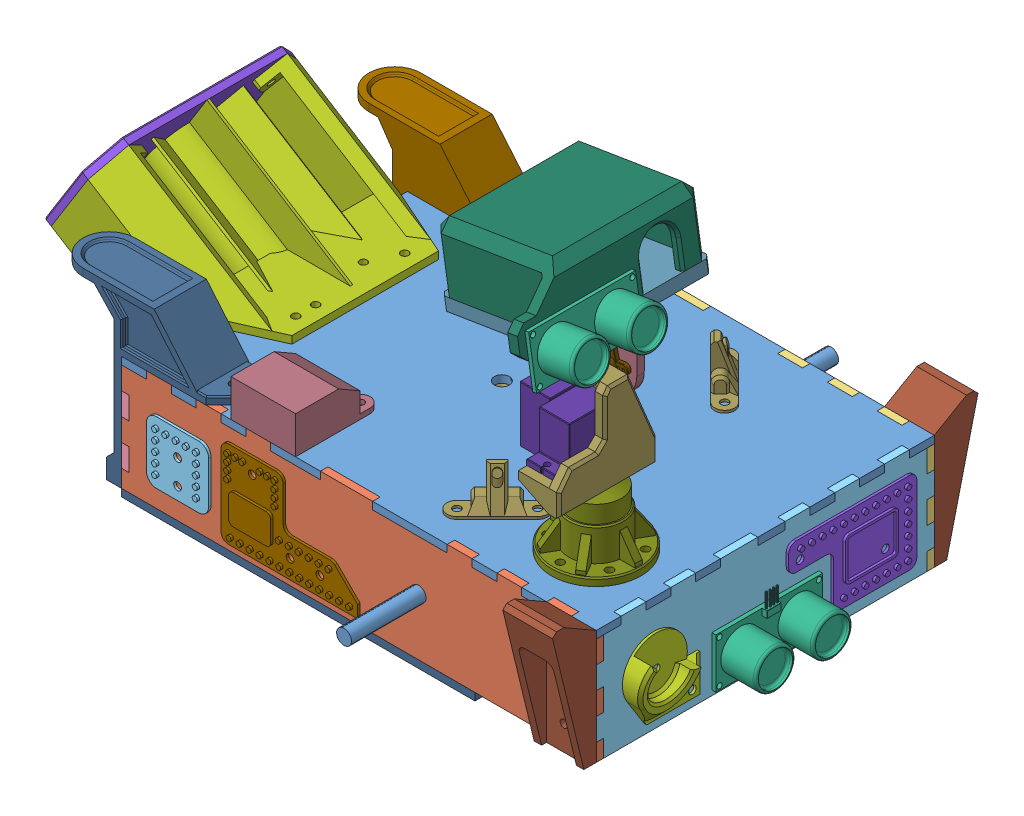
SolidWorks assembly bodySub-2, configuration Default. Lengths in mm.
Overall size (271.51 168.8 196).
43 component instances, 33 part files, 108 mates.
Components (placement in the parent):
- body-top-1: body-top [Default] at (-43.052 0 151.6865) x (1 0 0) z (0 1 0) size (191 136 3)
- body-right-1: body-right [Default] at (-43.052 -43 148.6865) size (191 46 3)
- body-left-1: body-left [Default] at (-43.052 -43 18.6865) x (-1 0 0) z (0 0 -1) size (191 46 3)
- body-rear-1: body-rear [Default] at (-43.052 -43 15.6865) x (0 0 -1) z (1 0 0) size (136 46 3)
- body-front-1: body-front [Default] at (147.948 -43 15.6865) x (0 0 1) z (-1 0 0) size (136 46 3)
- usSensor-1: usSensor [Default] at (-46.052 -45.55 62.1865) x (0 0 1) z (0 -1 0) size (43 15.6 26)
- usSensor-2: usSensor [Default] at (147.948 -21 62.1865) x (0 0 1) z (0 1 0) size (43 15.6 26)
- power-1: power [Default] at (-43.052 -43 151.6865) x (0 0 1) z (-1 0 0) size (84 85.03 90.67)
- powerCap-1: powerCap [Default] at (-74.8205 44.2822 15.6865) x (0 0 -1) z (-0.848048 0.529919 0) size (84 51.88 5)
- powerShoulder-left-1: powerShoulder-left [Default] at (-43.052 -43 15.6865) x (-1 0 0) z (0 0 -1) size (66.06 69 21)
- powerShoulder-right-1: powerShoulder-right [Default] at (-43.052 -43 109.6865) x (-1 0 0) z (0 0 -1) size (66.06 69 21)
- shoulder-1: shoulder [Default] at (127.948 -43 151.6865) size (20 53.5 17.6)
- shoulder-2: shoulder [Default] at (147.948 -43 15.6865) x (-1 0 0) z (0 0 -1) size (20 53.5 17.6)
- headSub-1: headSub [Default] at (131.8571 34.2972 110.6077) size (71.32 113.8 76.5) (flexible)
  - headServoMount-1: headServoMount [Default] at (-5.7591 24.2018 7.3288) x (0 0 1) z (1 0 0) size (39.75 36.12 28.6)
  - headMount-1: headMount [Default] at (-19.6139 25.1697 -5.5142) x (0.16009 -0.987102 0) z (0 0 -1) size (40 30 34)
  - headBaseplate-1: headBaseplate [Default] at (-50.728 44.8869 -23.5142) x (0 0 1) z (-0.987102 -0.16009 0) size (60 5 50)
  - headCanopy-1: headCanopy [Default] at (-6.1756 82.5045 -23.5142) x (0 0 1) z (0.16009 -0.987102 0) size (76.5 50 25)
  - usSensor-2: usSensor [Default] at (-0.5725 47.9559 49.9858) x (0 0 -1) z (0.16009 -0.987102 0) size (43 15.6 26)
  - mastMount-top-1: mastMount-top [Default] at (-11.9091 -31.2972 13.0788) size (36 28 36)
  - sg90Servo-1: sg90Servo [Default] at (-5.7591 24.0708 7.3288) x (0 0 1) z (1 0 0) size (32.7 29.37 12.3)
  - sg90Servo-2: sg90Servo [Default] at (-18.0591 24.5458 25.4538) x (0 -1 0) z (1 0 0) size (32.7 29.37 12.3)
  - sg90ServoHorn-star-1: sg90ServoHorn-star [Default] at (-27.3265 20.2151 -5.5142) x (0.16009 -0.987102 0) z (-0.987102 -0.16009 0) size (34.4 4 15.7)
- pivotAxle-1: pivotAxle [Default] at (76.448 -20 181.6865) x (-0.972905 0.231206 0) z (-0.231206 -0.972905 0) size (6 196 6)
- edison-arduino-1: edison-arduino [Default] at (-30.752 -13.38 66.6865) x (1 0 0) z (0 0 -1) size (127.2 12.67 72)
- diffMount-mid-1: diffMount-mid [Default] at (-43.052 0 151.6865) x (-1 0 0) z (0 -1 0) size (30 30 3)
- diffMount-bottom-1: diffMount-bottom [Default] at (-43.052 -3 151.6865) x (-1 0 0) z (0 -1 0) size (30 30 3)
- sideDetailA-left-1: sideDetailA-left [Default] at (-43.052 -43 15.6865) x (-1 0 0) z (0 0 -1) size (25 25 2)
- sideDetailB-1: sideDetailB [Default] at (-43.052 -43 15.6865) x (-1 0 0) z (0 0 -1) size (55 35 2)
- fontDetailA-1: fontDetailA [Default] at (147.948 -43 15.6865) x (0 0 -1) z (1 0 0) size (30.16 30.17 9.09)
- frontDetailB-1: frontDetailB [Default] at (147.948 -43 15.6865) x (0 0 -1) z (1 0 0) size (51.58 33 2)
- sideDetailB-mirr-1: sideDetailB-mirr [Default] at (-43.052 -43 151.6865) x (-1 0 0) z (0 0 -1) size (55 35 2)
- sideDetailA-left-2: sideDetailA-left [Default] at (3.948 -43 151.6865) size (25 25 2)
- bodyUnderCover-1: bodyUnderCover [Default] at (99.148 -43 15.6865) x (1 0 0) z (0 -1 0) size (142.2 136 9)
- underCoverMagnetMount-front-1: underCoverMagnetMount-front [Default] at (99.148 -43 15.6865) x (-1 0 0) z (0 1 0) size (7 7 11.3)
- underCoverMagnetMount-front-2: underCoverMagnetMount-front [Default] at (89.148 -43 151.6865) x (1 0 0) z (0 1 0) size (7 7 11.3)
- underCoverMagnetMount-front-3: underCoverMagnetMount-front [Default] at (-31.552 -43 15.6865) x (-1 0 0) z (0 1 0) size (7 7 11.3)
- underCoverMagnetMount-front-4: underCoverMagnetMount-front [Default] at (-41.552 -43 151.6865) x (1 0 0) z (0 1 0) size (7 7 11.3)
- topDetailA-1: topDetailA [Default] at (-43.052 3 151.6865) x (1 0 0) z (0 1 0) size (24.26 24.26 16)
- topDetailA-2: topDetailA [Default] at (108.7154 3 168.7548) x (0 0 -1) z (0 1 0) size (24.26 24.26 16)
- topDetailB-1: topDetailB [Default] at (-43.052 3 151.6865) x (1 0 0) z (0 1 0) size (26 34 15)
- topDetailCA-1: topDetailCA [Default] at (-46.5393 3 149.9052) x (1 0 0) z (0 1 0) size (20.56 18.54 22.66)
- topDetailCB-1: topDetailCB [Default] at (1.7026 61.1918 61.409) x (0.910046 -0.22774 0.34634) z (0.414508 0.5 -0.760384) size (46.65 24.53 4)
Mates (geometry in assembly coordinates):
- Coincident23: coincident anti-aligned: plane of body-front-1 through (147.948 -43 15.6865) normal (1 0 0); plane of usSensor-2 through (147.948 -21 62.1865) normal (-1 0 0)
- Coincident22: coincident anti-aligned: plane of body-top-1 through (144.948 -0.001 141.6865) normal (1 0 0); plane of body-front-1 through (144.948 -43 15.6865) normal (-1 0 0)
- Coincident21: coincident anti-aligned: plane of body-top-1 through (147.948 -0.001 141.6865) normal (0 0 -1); plane of body-front-1 through (147.949 -43 141.6865) normal (0 0 1)
- Coincident17: coincident anti-aligned: plane of body-top-1 through (-40.052 -0.001 35.6865) normal (-1 0 0); plane of body-rear-1 through (-40.052 -43 15.6865) normal (1 0 0)
- Coincident16: coincident anti-aligned: plane of body-top-1 through (-43.052 -0.001 25.6865) normal (0 0 1); plane of body-rear-1 through (-43.053 -43 25.6865) normal (0 0 -1)
- Coincident12: coincident anti-aligned: plane of body-top-1 through (-43.052 -0.001 18.6865) normal (0 0 -1); plane of body-left-1 through (-43.052 -43 18.6865) normal (0 0 1)
- Coincident11: coincident anti-aligned: plane of body-top-1 through (137.948 -0.001 15.6865) normal (-1 0 0); plane of body-left-1 through (137.948 3 15.6855) normal (1 0 0)
- Coincident7: coincident anti-aligned: plane of body-top-1 through (-43.052 -0.001 148.6865) normal (0 0 1); plane of body-right-1 through (-43.052 -43 148.6865) normal (0 0 -1)
- Coincident6: coincident anti-aligned: plane of body-top-1 through (-33.052 -0.001 151.6865) normal (1 0 0); plane of body-right-1 through (-33.052 0 151.6875) normal (-1 0 0)
- Coincident2: coincident anti-aligned: plane of body-top-1 through (-43.052 0 151.6865) normal (0 -1 0); plane of assembly through (0 0 0) normal (0 1 0)
- Concentric3: concentric aligned: cylinder of body-front-1 through (144.948 -22.5 103.6865) axis (1 0 0) radius 1.05; cylinder of usSensor-2 through (147.947 -22.5 103.6865) axis (1 0 0) radius 1.05
- Concentric4: concentric aligned: cylinder of body-front-1 through (144.948 -39.5 63.6865) axis (1 0 0) radius 1.05; cylinder of usSensor-2 through (147.947 -39.5 63.6865) axis (1 0 0) radius 1.05
- Coincident24: coincident anti-aligned: plane of power-1 through (-46.052 -43 151.6865) normal (-1 0 0); plane of usSensor-1 through (-46.052 -45.55 62.1865) normal (1 0 0)
- Concentric5: concentric anti-aligned: cylinder of body-top-1 through (-19.052 3 105.6173) axis (0 -1 0) radius 1.55; cylinder of power-1 through (-19.052 -43.001 105.6173) axis (0 1 0) radius 1.55
- Coincident25: coincident anti-aligned: plane of body-top-1 through (-43.052 3 151.6865) normal (0 1 0); plane of power-1 through (-13.052 3 151.6865) normal (0 -1 0)
- Concentric8: concentric aligned: cylinder of body-rear-1 through (-40.052 -27.05 63.6865) axis (-1 0 0) radius 1.05; cylinder of power-1 through (-40.0822 -27.05 63.6865) axis (-1 0 0) radius 1.05
- Concentric9: concentric aligned: cylinder of power-1 through (-40.0822 -27.05 63.6865) axis (-1 0 0) radius 1.05; cylinder of usSensor-1 through (-46.051 -27.05 63.6865) axis (-1 0 0) radius 1.05
- Concentric10: concentric aligned: cylinder of usSensor-1 through (-46.051 -27.05 103.6865) axis (-1 0 0) radius 1.05; cylinder of power-1 through (-40.0822 -27.05 103.6865) axis (-1 0 0) radius 1.05
- Coincident26: coincident anti-aligned: plane of power-1 through (-105.1238 -4.2132 151.6865) normal (-0.848048 0.529919 0); plane of powerCap-1 through (-74.8205 44.2822 15.6865) normal (0.848048 -0.529919 0)
- Concentric11: concentric anti-aligned: cylinder of powerCap-1 through (-83.4594 36.1202 56.0789) axis (0.848048 -0.529919 0) radius 1.55; cylinder of power-1 through (2.7341 -17.7395 56.0789) axis (-0.848048 0.529919 0) radius 1.55
- Concentric12: concentric anti-aligned: cylinder of power-1 through (2.7341 -17.7395 111.2941) axis (-0.848048 0.529919 0) radius 1.55; cylinder of powerCap-1 through (-83.4594 36.1202 111.2941) axis (0.848048 -0.529919 0) radius 1.55
- Coincident27: coincident anti-aligned: plane of body-rear-1 through (-43.052 -43 15.6865) normal (-1 0 0); plane of powerShoulder-right-1 through (-43.052 -43 151.6865) normal (1 0 0)
- Coincident28: coincident anti-aligned: plane of body-top-1 through (-43.052 3 151.6865) normal (0 1 0); plane of powerShoulder-right-1 through (-43.052 3 81.1263) normal (0 -1 0)
- Concentric13: concentric anti-aligned: cylinder of body-top-1 through (-8.052 3 135.6865) axis (0 -1 0) radius 1.55; cylinder of powerShoulder-right-1 through (-8.052 -43.001 135.6865) axis (0 1 0) radius 1.55
- Coincident29: coincident anti-aligned: plane of body-rear-1 through (-43.052 -43 15.6865) normal (-1 0 0); plane of powerShoulder-left-1 through (-43.052 -43 15.6865) normal (1 0 0)
- Coincident30: coincident anti-aligned: plane of body-top-1 through (-43.052 3 151.6865) normal (0 1 0); plane of powerShoulder-left-1 through (-43.052 3 86.2467) normal (0 -1 0)
- Concentric14: concentric anti-aligned: cylinder of body-top-1 through (-8.052 3 31.6865) axis (0 -1 0) radius 1.55; cylinder of powerShoulder-left-1 through (-8.052 -43.001 31.6865) axis (0 1 0) radius 1.55
- Coincident31: coincident anti-aligned: plane of body-left-1 through (-43.052 -43 15.6865) normal (0 0 -1); plane of shoulder-2 through (127.948 -43 15.6865) normal (0 0 1)
- Concentric15: concentric anti-aligned: cylinder of body-left-1 through (137.948 -13 15.6865) axis (0 0 1) radius 1.55; cylinder of shoulder-2 through (137.948 -13 12.6865) axis (0 0 -1) radius 1.55
- Concentric16: concentric anti-aligned: cylinder of body-left-1 through (137.948 -33 15.6865) axis (0 0 1) radius 1.55; cylinder of shoulder-2 through (137.948 -33 12.6865) axis (0 0 -1) radius 1.55
- Coincident32: coincident anti-aligned: plane of body-right-1 through (-43.052 -43 151.6865) normal (0 0 1); plane of shoulder-1 through (147.948 -43 151.6865) normal (0 0 -1)
- Concentric17: concentric anti-aligned: cylinder of body-right-1 through (137.948 -13 151.6865) axis (0 0 -1) radius 1.55; cylinder of shoulder-1 through (137.948 -13 154.6865) axis (0 0 1) radius 1.55
- Concentric18: concentric anti-aligned: cylinder of body-right-1 through (137.948 -33 151.6865) axis (0 0 -1) radius 1.55; cylinder of shoulder-1 through (137.948 -33 154.6865) axis (0 0 1) radius 1.55
- Coincident33: coincident anti-aligned: plane of body-top-1 through (-43.052 3 151.6865) normal (0 1 0); plane of headSub-1/mastMount-top-1 through (119.948 3 123.6865) normal (0 -1 0)
- Concentric19: concentric anti-aligned: cylinder of body-top-1 through (132.5054 3 116.4365) axis (0 -1 0) radius 1.55; cylinder of headSub-1/mastMount-top-1 through (132.5054 6 116.4365) axis (0 1 0) radius 1.55
- Concentric20: concentric anti-aligned: cylinder of body-top-1 through (107.3906 3 130.9365) axis (0 -1 0) radius 1.55; cylinder of headSub-1/mastMount-top-1 through (107.3906 6 130.9365) axis (0 1 0) radius 1.55
- Coincident34: coincident aligned: plane of body-top-1 through (-43.052 3 151.6865) normal (0 1 0); plane of body-front-1 through (144.948 3 151.6865) normal (0 1 0)
- Coincident35: coincident aligned: plane of body-top-1 through (-43.052 3 151.6865) normal (0 1 0); plane of body-left-1 through (-43.052 3 15.6865) normal (0 1 0)
- Coincident36: coincident aligned: plane of body-top-1 through (-43.052 3 151.6865) normal (0 1 0); plane of body-rear-1 through (-40.052 3 15.6865) normal (0 1 0)
- Coincident37: coincident aligned: plane of body-top-1 through (-43.052 3 151.6865) normal (0 1 0); plane of body-right-1 through (147.948 3 151.6865) normal (0 1 0)
- Concentric21: concentric anti-aligned: cylinder of body-left-1 through (76.448 -20 18.6875) axis (0 0 -1) radius 3; cylinder of pivotAxle-1 through (76.448 -20 -14.3135) axis (0 0 1) radius 3
- Symmetric2: symmetric aligned: plane of body-top-1 through (-43.052 0 83.6865) normal (0 0 -1); plane of pivotAxle-1 through (76.448 -20 -14.3135) normal (0 0 -1); plane of pivotAxle-1 through (76.448 -20 181.6865) normal (0 0 1)
- Parallel1: parallel anti-aligned: plane of body-top-1 through (-43.052 0 151.6865) normal (0 -1 0); plane of edison-arduino-1 through (-30.752 -13.38 66.6865) normal (0 1 0)
- Parallel2: parallel anti-aligned: plane of body-rear-1 through (-40.052 -43 15.6865) normal (1 0 0); plane of edison-arduino-1 through (-30.752 -15 66.6865) normal (-1 0 0)
- Distance2: distance = 2 mm anti-aligned: plane of edison-arduino-1 through (-30.752 -15 66.6865) normal (0 -1 0); cylinder of pivotAxle-1 through (76.448 -20 -14.3135) axis (0 0 1) radius 3
- Distance3: distance = 1 mm anti-aligned: plane of edison-arduino-1 through (80.448 -26 134.6865) normal (-1 0 0); cylinder of pivotAxle-1 through (76.448 -20 -14.3135) axis (0 0 1) radius 3
- Distance4: distance = 10 mm anti-aligned: plane of edison-arduino-1 through (-30.752 -15 138.6865) normal (0 0 1); plane of body-right-1 through (-43.052 -43 148.6865) normal (0 0 -1)
- InPlace1: in place: plane of body-top-1 through (-43.052 0 151.6865) normal (0 -1 0); plane of ? through (0 0 0) normal (0 -1 0); moOrthogonalPlaneRef_w of body-top-1 through (-43.052 0 151.6865) normal (0 -1 0); unknown of ?; plane of body-top-1 through (-43.052 0 151.6865) normal (0 -1 0); line of ? through (55 -55 0) axis (0 0 -1); plane of body-top-1 through (-43.052 0 151.6865) normal (0 -1 0); unknown of diffMount-mid-1
- Coincident41: coincident aligned: plane of body-top-1; plane of diffMount-mid-1
- Coincident42: coincident aligned: moOrthogonalPlaneRef_w of body-top-1 through (-43.052 0 151.6865) normal (0 0 -1); plane of diffMount-mid-1
- Coincident43: coincident anti-aligned: moOrthogonalPlaneRef_w of body-top-1 through (-43.052 0 151.6865) normal (1 0 0); plane of diffMount-mid-1
- InPlace2: in place: plane of diffMount-mid-1 through (41.948 -3 83.6865) normal (0 -1 0); plane of ? through (0 -3 0) normal (0 -1 0); plane of diffMount-mid-1 through (41.948 -3 83.6865) normal (0 -1 0); unknown of ?; plane of diffMount-mid-1 through (41.948 -3 83.6865) normal (0 -1 0); line of ? through (-55 0 -3) axis (0 -1 0); plane of diffMount-mid-1 through (41.948 -3 83.6865) normal (0 -1 0); unknown of diffMount-bottom-1
- Coincident44: coincident aligned: plane of diffMount-mid-1; plane of diffMount-bottom-1
- Coincident45: coincident aligned: moOrthogonalPlaneRef_w of diffMount-mid-1 through (-43.052 -3 151.6865) normal (0 0 -1); plane of diffMount-bottom-1
- Coincident46: coincident anti-aligned: moOrthogonalPlaneRef_w of diffMount-mid-1 through (-43.052 -3 151.6865) normal (1 0 0); plane of diffMount-bottom-1
- InPlace3: in place: plane of body-left-1 through (-43.052 -43 15.6865) normal (0 0 -1); plane of ? through (0 0 15.6865) normal (0 0 -1); plane of body-left-1 through (-43.052 -43 15.6865) normal (0 0 -1); unknown of ?; plane of body-left-1 through (-43.052 -43 15.6865) normal (0 0 -1); plane of ? through (0 0 15.6865) normal (-1 0 0); plane of body-left-1 through (-43.052 -43 15.6865) normal (0 0 -1); unknown of ?
- Coincident47: coincident aligned: plane of body-left-1; plane of sideDetailA-left-1
- Coincident48: coincident aligned: moOrthogonalPlaneRef_w of body-left-1 through (-43.052 -43 15.6865) normal (0 1 0); plane of sideDetailA-left-1
- Coincident49: coincident anti-aligned: moOrthogonalPlaneRef_w of body-left-1 through (-43.052 -43 15.6865) normal (1 0 0); plane of sideDetailA-left-1 through (-43.052 -43 15.6865) normal (-1 0 0)
- InPlace4: in place: plane of body-left-1 through (-43.052 -43 15.6865) normal (0 0 -1); plane of ? through (0 0 15.6865) normal (0 0 -1); plane of body-left-1 through (-43.052 -43 15.6865) normal (0 0 -1); unknown of ?; plane of body-left-1 through (-43.052 -43 15.6865) normal (0 0 -1); plane of ? through (0 0 15.6865) normal (-1 0 0); plane of body-left-1 through (-43.052 -43 15.6865) normal (0 0 -1); unknown of ?
- Coincident50: coincident aligned: plane of body-left-1; plane of sideDetailB-1
- Coincident51: coincident aligned: moOrthogonalPlaneRef_w of body-left-1 through (-43.052 -43 15.6865) normal (0 1 0); plane of sideDetailB-1
- Coincident52: coincident anti-aligned: moOrthogonalPlaneRef_w of body-left-1 through (-43.052 -43 15.6865) normal (1 0 0); plane of sideDetailB-1 through (-43.052 -43 15.6865) normal (-1 0 0)
- InPlace5: in place: plane of body-front-1 through (147.948 -43 15.6865) normal (1 0 0); plane of ? through (147.948 0 0) normal (1 0 0); plane of body-front-1 through (147.948 -43 15.6865) normal (1 0 0); line of ? through (-55 147.948 0) axis (0 0 1); plane of body-front-1 through (147.948 -43 15.6865) normal (1 0 0); plane of ? through (147.948 0 0) normal (0 0 -1); plane of body-front-1 through (147.948 -43 15.6865) normal (1 0 0); unknown of ?
- Coincident53: coincident aligned: plane of body-front-1; plane of fontDetailA-1
- Coincident54: coincident aligned: moOrthogonalPlaneRef_w of body-front-1 through (147.948 -43 15.6865) normal (0 1 0); plane of fontDetailA-1
- Coincident55: coincident anti-aligned: moOrthogonalPlaneRef_w of body-front-1 through (147.948 -43 15.6865) normal (0 0 1); plane of fontDetailA-1 through (147.948 -43 15.6865) normal (0 0 -1)
- InPlace6: in place: plane of body-front-1 through (147.948 -43 15.6865) normal (1 0 0); plane of ? through (147.948 0 0) normal (1 0 0); plane of body-front-1 through (147.948 -43 15.6865) normal (1 0 0); line of ? through (-55 147.948 0) axis (0 0 1); plane of body-front-1 through (147.948 -43 15.6865) normal (1 0 0); plane of ? through (147.948 0 0) normal (0 0 -1); plane of body-front-1 through (147.948 -43 15.6865) normal (1 0 0); unknown of ?
- Coincident56: coincident aligned: plane of body-front-1; plane of frontDetailB-1
- Coincident57: coincident aligned: moOrthogonalPlaneRef_w of body-front-1 through (147.948 -43 15.6865) normal (0 1 0); plane of frontDetailB-1
- Coincident58: coincident anti-aligned: moOrthogonalPlaneRef_w of body-front-1 through (147.948 -43 15.6865) normal (0 0 1); plane of frontDetailB-1 through (147.948 -43 15.6865) normal (0 0 -1)
- Coincident59: coincident anti-aligned: plane of body-right-1 through (-43.052 -43 151.6865) normal (0 0 1); plane of sideDetailB-mirr-1 through (-43.052 -43 151.6865) normal (0 0 -1)
- Concentric22: concentric aligned: cylinder of body-right-1 through (10.448 -11 148.6855) axis (0 0 1) radius 1.55; cylinder of sideDetailB-mirr-1 through (10.448 -11 151.6855) axis (0 0 1) radius 1.55
- Concentric23: concentric aligned: cylinder of body-right-1 through (37.7054 -32.5 148.6855) axis (0 0 1) radius 1.55; cylinder of sideDetailB-mirr-1 through (37.7054 -32.5 151.6855) axis (0 0 1) radius 1.55
- Concentric24: concentric aligned: cylinder of body-right-1 through (-19.552 -20 148.6855) axis (0 0 1) radius 1.55; cylinder of sideDetailA-left-2 through (-19.552 -20 151.6855) axis (0 0 1) radius 1.55
- Concentric25: concentric aligned: cylinder of body-right-1 through (-19.552 -30 148.6855) axis (0 0 1) radius 1.55; cylinder of sideDetailA-left-2 through (-19.552 -30 151.6855) axis (0 0 1) radius 1.55
- Coincident60: coincident anti-aligned: plane of body-right-1 through (-43.052 -43 151.6865) normal (0 0 1); plane of sideDetailA-left-2 through (3.948 -43 151.6865) normal (0 0 -1)
- Coincident62: coincident aligned: plane of body-rear-1 through (-43.052 -43 15.6865) normal (-1 0 0); plane of bodyUnderCover-1 through (-43.052 -49 15.6865) normal (-1 0 0)
- Coincident64: coincident aligned: plane of body-left-1 through (-43.052 -43 15.6865) normal (0 0 -1); plane of bodyUnderCover-1 through (99.148 -49 15.6865) normal (0 0 -1)
- Coincident65: coincident anti-aligned: plane of body-left-1 through (147.948 -43 15.6865) normal (0 -1 0); plane of bodyUnderCover-1 through (99.148 -43 15.6865) normal (0 1 0)
- InPlace7: in place: plane of bodyUnderCover-1 through (99.148 -43 15.6865) normal (0 1 0); plane of ? through (0 -43 0) normal (0 1 0); plane of bodyUnderCover-1 through (99.148 -43 15.6865) normal (0 1 0); plane of ? through (0 -43 0) normal (0 0 -1); plane of bodyUnderCover-1 through (99.148 -43 15.6865) normal (0 1 0); line of ? through (-55 0 -43) axis (0 1 0); plane of bodyUnderCover-1 through (99.148 -43 15.6865) normal (0 1 0); unknown of underCoverMagnetMount-front-1
- Coincident66: coincident aligned: plane of bodyUnderCover-1; plane of underCoverMagnetMount-front-1
- Coincident67: coincident aligned: moOrthogonalPlaneRef_w of bodyUnderCover-1 through (99.148 -43 15.6865) normal (0 0 1); plane of underCoverMagnetMount-front-1
- Coincident68: coincident anti-aligned: moOrthogonalPlaneRef_w of bodyUnderCover-1 through (99.148 -43 15.6865) normal (1 0 0); plane of underCoverMagnetMount-front-1
- Coincident69: coincident anti-aligned: plane of body-right-1 through (-43.052 -43 148.6865) normal (0 0 -1); plane of underCoverMagnetMount-front-2 through (89.148 -40.7 148.6865) normal (0 0 1)
- Concentric27: concentric anti-aligned: cylinder of bodyUnderCover-1 through (94.148 -45.3 145.1865) axis (0 1 0) radius 1.55; cylinder of underCoverMagnetMount-front-2 through (94.148 -40.7 145.1865) axis (0 -1 0) radius 1.55
- Coincident70: coincident anti-aligned: plane of bodyUnderCover-1 through (99.148 -43 15.6865) normal (0 1 0); plane of underCoverMagnetMount-front-2 through (89.148 -43 151.6865) normal (0 -1 0)
- Coincident71: coincident anti-aligned: plane of body-left-1 through (-43.052 -43 18.6865) normal (0 0 1); plane of underCoverMagnetMount-front-3 through (-31.552 -40.7 18.6865) normal (0 0 -1)
- Concentric28: concentric anti-aligned: cylinder of bodyUnderCover-1 through (-36.552 -45.3 22.1865) axis (0 1 0) radius 1.55; cylinder of underCoverMagnetMount-front-3 through (-36.552 -40.7 22.1865) axis (0 -1 0) radius 1.55
- Coincident72: coincident anti-aligned: plane of bodyUnderCover-1 through (99.148 -43 15.6865) normal (0 1 0); plane of underCoverMagnetMount-front-3 through (-31.552 -43 15.6865) normal (0 -1 0)
- Coincident73: coincident anti-aligned: plane of body-right-1 through (-43.052 -43 148.6865) normal (0 0 -1); plane of underCoverMagnetMount-front-4 through (-41.552 -40.7 148.6865) normal (0 0 1)
- Concentric29: concentric anti-aligned: cylinder of bodyUnderCover-1 through (-36.552 -45.3 145.1865) axis (0 1 0) radius 1.55; cylinder of underCoverMagnetMount-front-4 through (-36.552 -40.7 145.1865) axis (0 -1 0) radius 1.55
- Coincident74: coincident anti-aligned: plane of bodyUnderCover-1 through (99.148 -43 15.6865) normal (0 1 0); plane of underCoverMagnetMount-front-4 through (-41.552 -43 151.6865) normal (0 -1 0)
- InPlace8: in place: plane of body-top-1 through (-43.052 3 151.6865) normal (0 1 0); plane of ? through (0 3 0) normal (0 1 0); plane of body-top-1 through (-43.052 3 151.6865) normal (0 1 0); plane of ? through (0 3 0) normal (0 0 -1); plane of body-top-1 through (-43.052 3 151.6865) normal (0 1 0); line of ? through (-55 0 3) axis (0 1 0); plane of body-top-1 through (-43.052 3 151.6865) normal (0 1 0); unknown of ?
- Coincident75: coincident aligned: plane of body-top-1; plane of topDetailA-1
- Coincident76: coincident aligned: moOrthogonalPlaneRef_w of body-top-1 through (-43.052 3 151.6865) normal (0 0 -1); plane of topDetailA-1 through (-43.052 3 151.6865) normal (0 0 -1)
- Coincident77: coincident anti-aligned: moOrthogonalPlaneRef_w of body-top-1 through (-43.052 3 151.6865) normal (-1 0 0); plane of topDetailA-1
- Coincident78: coincident anti-aligned: plane of body-top-1 through (-43.052 3 151.6865) normal (0 1 0); plane of topDetailA-2 through (108.7154 3 168.7548) normal (0 -1 0)
- Perpendicular1: perpendicular: plane of topDetailA-2 through (95.2501 4 52.9763) normal (-0.707107 0 0.707107); plane of topDetailA-1 through (78.3833 4 143.8781) normal (0.707107 0 0.707107)
- InPlace9: in place: plane of body-top-1 through (-43.052 3 151.6865) normal (0 1 0); plane of ? through (0 3 0) normal (0 1 0); plane of body-top-1 through (-43.052 3 151.6865) normal (0 1 0); plane of ? through (0 3 0) normal (0 0 -1); plane of body-top-1 through (-43.052 3 151.6865) normal (0 1 0); line of ? through (-55 0 3) axis (0 1 0); plane of body-top-1 through (-43.052 3 151.6865) normal (0 1 0); unknown of ?
- Coincident80: coincident aligned: plane of body-top-1; plane of topDetailB-1
- Coincident81: coincident aligned: moOrthogonalPlaneRef_w of body-top-1 through (-43.052 3 151.6865) normal (0 0 -1); plane of topDetailB-1 through (-43.052 3 151.6865) normal (0 0 -1)
- Coincident82: coincident anti-aligned: moOrthogonalPlaneRef_w of body-top-1 through (-43.052 3 151.6865) normal (-1 0 0); plane of topDetailB-1
- Coincident86: coincident anti-aligned: plane of body-top-1 through (-43.052 3 151.6865) normal (0 1 0); plane of topDetailCA-1 through (-46.5393 3 149.9052) normal (0 -1 0)
- InPlace11: in place: plane of topDetailCA-1 through (22.6249 60.6918 73.8008) normal (0.414508 0.5 -0.760384); plane of ? through (-6.7949 -8.1964 12.4648) normal (0.414508 0.5 -0.760384); plane of topDetailCA-1 through (22.6249 60.6918 73.8008) normal (0.414508 0.5 -0.760384); unknown of ?; plane of topDetailCA-1 through (22.6249 60.6918 73.8008) normal (0.414508 0.5 -0.760384); unknown of ?; plane of topDetailCA-1 through (23.0394 61.1918 73.0404) normal (0.414508 0.5 -0.760384); unknown of topDetailCB-1
- Coincident87: coincident aligned: plane of topDetailCA-1; plane of topDetailCB-1
- Coincident88: coincident aligned: moOrthogonalPlaneRef_w of topDetailCA-1 through (1.7026 61.1918 61.409) normal (0 -0.835544 -0.549423); plane of topDetailCB-1
- Coincident89: coincident anti-aligned: moOrthogonalPlaneRef_w of topDetailCA-1 through (1.7026 61.1918 61.409) normal (-0.910046 0.22774 -0.34634); plane of topDetailCB-1
